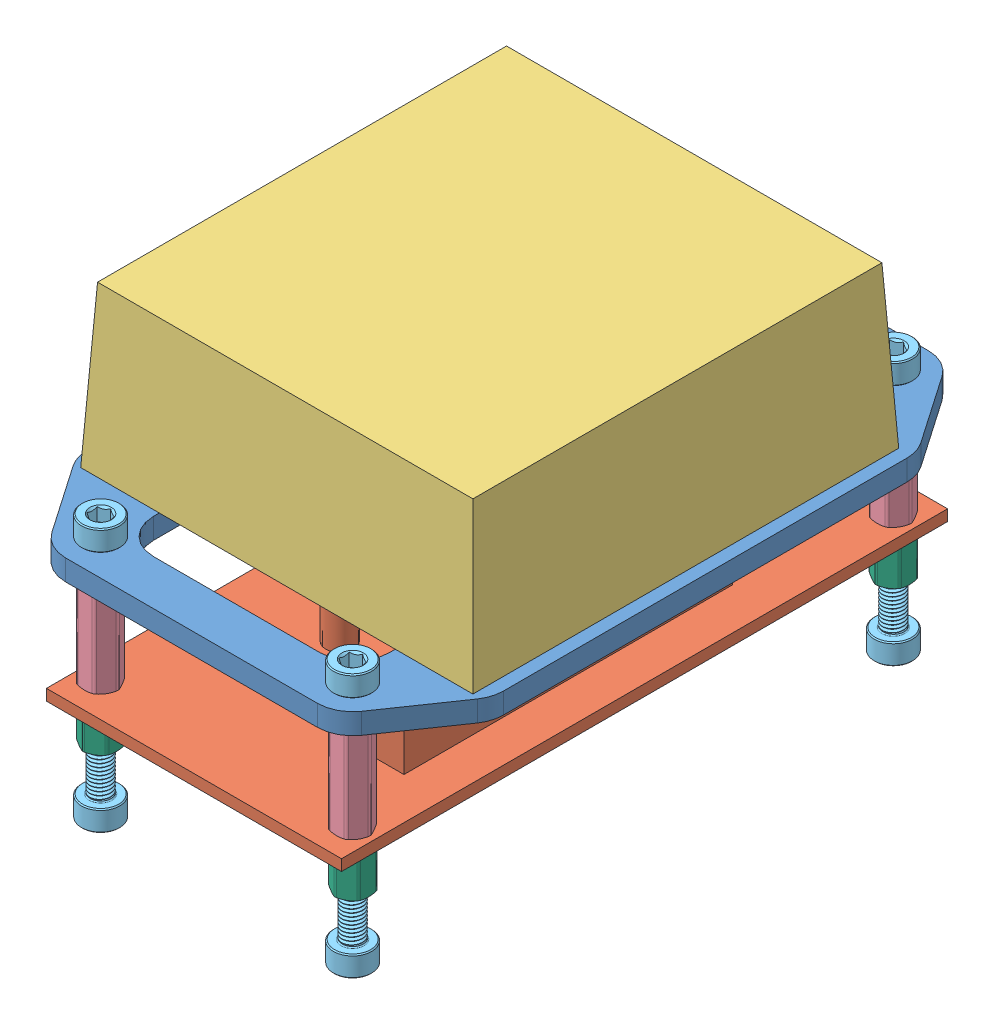
SolidWorks assembly GPS Assembly, configuration Default. Lengths in mm.
Overall size (60 58.13 88).
19 component instances, 6 part files, 36 mates.
Components (placement in the parent):
- GPS Bracket-1: GPS Bracket [Default] at (-19.8291 35.7589 91.6972) size (60 3 88)
- GPS-1: GPS [Default] at (-11.0841 19.1589 91.3522) size (42.51 15.6 87.31)
- GPS Antenna-2: GPS Antenna [Default] at (-18.1499 38.7589 79.3441) size (56.5 23.14 61.34)
- 94868A722_Female Threaded Hex Standoff-1: 94868A722_Female Threaded Hex Standoff [94868A722] at (-7.9791 28.2589 86.6472) x (1 0 0) z (0 -1 0) size (5.06 4.5 15.05)
- 94868A722_Female Threaded Hex Standoff-2: 94868A722_Female Threaded Hex Standoff [94868A722] at (28.3209 28.2589 8.7472) x (1 0 0) z (0 -1 0) size (5.06 4.5 15.05)
- 94868A722_Female Threaded Hex Standoff-3: 94868A722_Female Threaded Hex Standoff [94868A722] at (-7.9791 28.2589 8.7472) x (1 0 0) z (0 -1 0) size (5.06 4.5 15.05)
- 94868A722_Female Threaded Hex Standoff-4: 94868A722_Female Threaded Hex Standoff [94868A722] at (28.3209 28.2589 86.6472) x (1 0 0) z (0 -1 0) size (5.06 4.5 15.05)
- 91290A113_Alloy Steel Socket Head Screw-1: 91290A113_Alloy Steel Socket Head Screw [91290A113] at (-7.9791 36.2589 86.6472) x (1 0 0) z (0 1 0) size (5.5 5.5 11.27)
- 91290A113_Alloy Steel Socket Head Screw-2: 91290A113_Alloy Steel Socket Head Screw [91290A113] at (-7.9791 9.3089 8.7472) x (-0.837169 0 -0.546944) z (0 -1 0) size (5.5 5.5 11.27)
- 91290A113_Alloy Steel Socket Head Screw-3: 91290A113_Alloy Steel Socket Head Screw [91290A113] at (-7.9791 9.3089 86.6472) x (-0.837169 0 -0.546944) z (0 -1 0) size (5.5 5.5 11.27)
- 91290A113_Alloy Steel Socket Head Screw-4: 91290A113_Alloy Steel Socket Head Screw [91290A113] at (28.3209 9.3089 86.6472) x (-0.837169 0 -0.546944) z (0 -1 0) size (5.5 5.5 11.27)
- 91290A113_Alloy Steel Socket Head Screw-5: 91290A113_Alloy Steel Socket Head Screw [91290A113] at (28.3209 36.2589 8.7472) x (1 0 0) z (0 1 0) size (5.5 5.5 11.27)
- 91290A113_Alloy Steel Socket Head Screw-6: 91290A113_Alloy Steel Socket Head Screw [91290A113] at (28.3209 9.3089 8.7472) x (-0.837169 0 -0.546944) z (0 -1 0) size (5.5 5.5 11.27)
- 91290A113_Alloy Steel Socket Head Screw-7: 91290A113_Alloy Steel Socket Head Screw [91290A113] at (-7.9791 36.2589 8.7472) x (1 0 0) z (0 1 0) size (5.5 5.5 11.27)
- 91290A113_Alloy Steel Socket Head Screw-8: 91290A113_Alloy Steel Socket Head Screw [91290A113] at (28.3209 36.2589 86.6472) x (1 0 0) z (0 1 0) size (5.5 5.5 11.27)
- 93655A093_Male-Female Threaded Hex Standoff-1: 93655A093_Male-Female Threaded Hex Standoff [93655A093] at (28.3209 19.1589 8.7472) x (-1 0 0) z (0 -1 0) size (4.5 5.08 10.78)
- 93655A093_Male-Female Threaded Hex Standoff-2: 93655A093_Male-Female Threaded Hex Standoff [93655A093] at (28.3209 19.1589 86.6472) x (-1 0 0) z (0 -1 0) size (4.5 5.08 10.78)
- 93655A093_Male-Female Threaded Hex Standoff-3: 93655A093_Male-Female Threaded Hex Standoff [93655A093] at (-7.9791 19.1589 86.6472) x (-1 0 0) z (0 -1 0) size (4.5 5.08 10.78)
- 93655A093_Male-Female Threaded Hex Standoff-4: 93655A093_Male-Female Threaded Hex Standoff [93655A093] at (-7.9791 19.1589 8.7472) x (-1 0 0) z (0 -1 0) size (4.5 5.08 10.78)
Mates (geometry in assembly coordinates):
- Concentric1: concentric aligned: cylinder of GPS Bracket-1 through (28.3209 38.7589 86.6472) axis (0 -1 0) radius 1.75; cylinder of GPS-1 through (28.3209 20.7589 86.6472) axis (0 -1 0) radius 1.77
- Concentric2: concentric aligned: cylinder of GPS Bracket-1 through (-7.9791 38.7589 8.7472) axis (0 -1 0) radius 1.75; cylinder of GPS-1 through (-7.9791 20.7589 8.7472) axis (0 -1 0) radius 1.77
- Coincident6: coincident anti-aligned: plane of GPS Bracket-1 through (-19.8291 35.7589 91.6972) normal (0 -1 0); plane of 94868A722_Female Threaded Hex Standoff-1 through (-7.9791 35.7589 86.6472) normal (0 1 0)
- Coincident7: coincident anti-aligned: plane of GPS Bracket-1 through (-19.8291 35.7589 91.6972) normal (0 -1 0); plane of 94868A722_Female Threaded Hex Standoff-4 through (28.3209 35.7589 86.6472) normal (0 1 0)
- Coincident8: coincident anti-aligned: plane of GPS Bracket-1 through (-19.8291 35.7589 91.6972) normal (0 -1 0); plane of 94868A722_Female Threaded Hex Standoff-2 through (28.3209 35.7589 8.7472) normal (0 1 0)
- Coincident9: coincident anti-aligned: plane of GPS Bracket-1 through (-19.8291 35.7589 91.6972) normal (0 -1 0); plane of 94868A722_Female Threaded Hex Standoff-3 through (-7.9791 35.7589 8.7472) normal (0 1 0)
- Concentric7: concentric aligned: cylinder of GPS Bracket-1 through (28.3209 38.7589 8.7472) axis (0 -1 0) radius 1.75; cone of 94868A722_Female Threaded Hex Standoff-2 through (28.3209 35.7589 8.7472) axis (0 -1 0)
- Concentric8: concentric aligned: cylinder of GPS Bracket-1 through (-7.9791 38.7589 8.7472) axis (0 -1 0) radius 1.75; cone of 94868A722_Female Threaded Hex Standoff-3 through (-7.9791 35.7589 8.7472) axis (0 -1 0)
- Concentric9: concentric aligned: cylinder of GPS Bracket-1 through (28.3209 38.7589 86.6472) axis (0 -1 0) radius 1.75; cone of 94868A722_Female Threaded Hex Standoff-4 through (28.3209 35.7589 86.6472) axis (0 -1 0)
- Concentric10: concentric aligned: cylinder of GPS Bracket-1 through (-7.9791 38.7589 86.6472) axis (0 -1 0) radius 1.75; cone of 94868A722_Female Threaded Hex Standoff-1 through (-7.9791 35.7589 86.6472) axis (0 -1 0)
- Coincident10: coincident anti-aligned: plane of GPS Bracket-1 through (-19.8291 38.7589 91.6972) normal (0 1 0); plane of GPS Antenna-2 through (-18.1499 38.7589 79.3441) normal (0 -1 0)
- Coincident11: coincident anti-aligned: plane of GPS-1 through (-11.0841 20.7589 91.3522) normal (0 1 0); plane of 94868A722_Female Threaded Hex Standoff-4 through (28.3209 20.7589 86.6472) normal (0 -1 0)
- Coincident12: coincident anti-aligned: plane of GPS Bracket-1 through (-19.8291 38.7589 91.6972) normal (0 1 0); plane of 91290A113_Alloy Steel Socket Head Screw-8 through (28.3209 38.7589 84.0472) normal (0 -1 0)
- Coincident13: coincident anti-aligned: plane of GPS Bracket-1 through (-19.8291 38.7589 91.6972) normal (0 1 0); plane of 91290A113_Alloy Steel Socket Head Screw-1 through (-7.9791 38.7589 84.0472) normal (0 -1 0)
- Coincident14: coincident anti-aligned: plane of GPS Bracket-1 through (-19.8291 38.7589 91.6972) normal (0 1 0); plane of 91290A113_Alloy Steel Socket Head Screw-7 through (-7.9791 38.7589 6.1472) normal (0 -1 0)
- Coincident16: coincident anti-aligned: plane of GPS Bracket-1 through (-19.8291 38.7589 91.6972) normal (0 1 0); plane of 91290A113_Alloy Steel Socket Head Screw-5 through (28.3209 38.7589 6.1472) normal (0 -1 0)
- Concentric12: concentric aligned: cylinder of GPS Bracket-1 through (-7.9791 38.7589 86.6472) axis (0 -1 0) radius 1.75; cylinder of 91290A113_Alloy Steel Socket Head Screw-1 through (-7.9791 30.7589 86.6472) axis (0 -1 0) radius 2.75
- Concentric13: concentric aligned: cylinder of GPS Bracket-1 through (28.3209 38.7589 86.6472) axis (0 -1 0) radius 1.75; cylinder of 91290A113_Alloy Steel Socket Head Screw-8 through (28.3209 30.7589 86.6472) axis (0 -1 0) radius 2.75
- Concentric14: concentric aligned: cylinder of GPS Bracket-1 through (-7.9791 38.7589 8.7472) axis (0 -1 0) radius 1.75; cylinder of 91290A113_Alloy Steel Socket Head Screw-7 through (-7.9791 30.7589 8.7472) axis (0 -1 0) radius 2.75
- Concentric15: concentric aligned: cylinder of GPS Bracket-1 through (28.3209 38.7589 8.7472) axis (0 -1 0) radius 1.75; cylinder of 91290A113_Alloy Steel Socket Head Screw-5 through (28.3209 30.7589 8.7472) axis (0 -1 0) radius 2.75
- Concentric17: concentric anti-aligned: cylinder of GPS-1 through (28.3209 20.7589 8.7472) axis (0 -1 0) radius 1.77; cone of 93655A093_Male-Female Threaded Hex Standoff-1 through (28.3209 19.1589 8.7472) axis (0 1 0)
- Concentric18: concentric anti-aligned: cylinder of GPS-1 through (-7.9791 20.7589 8.7472) axis (0 -1 0) radius 1.77; cone of 93655A093_Male-Female Threaded Hex Standoff-4 through (-7.9791 19.1589 8.7472) axis (0 1 0)
- Concentric19: concentric anti-aligned: cylinder of GPS-1 through (28.3209 20.7589 86.6472) axis (0 -1 0) radius 1.77; cone of 93655A093_Male-Female Threaded Hex Standoff-2 through (28.3209 19.1589 86.6472) axis (0 1 0)
- Concentric20: concentric anti-aligned: cylinder of GPS-1 through (-7.9791 20.7589 86.6472) axis (0 -1 0) radius 1.77; cone of 93655A093_Male-Female Threaded Hex Standoff-3 through (-7.9791 19.1589 86.6472) axis (0 1 0)
- Coincident21: coincident anti-aligned: plane of GPS-1 through (-11.0841 19.1589 91.3522) normal (0 -1 0); plane of 93655A093_Male-Female Threaded Hex Standoff-3 through (-7.9791 19.1589 85.222) normal (0 1 0)
- Coincident22: coincident anti-aligned: plane of GPS-1 through (-11.0841 19.1589 91.3522) normal (0 -1 0); plane of 93655A093_Male-Female Threaded Hex Standoff-2 through (28.3209 19.1589 85.222) normal (0 1 0)
- Coincident23: coincident anti-aligned: plane of GPS-1 through (-11.0841 19.1589 91.3522) normal (0 -1 0); plane of 93655A093_Male-Female Threaded Hex Standoff-4 through (-7.9791 19.1589 7.322) normal (0 1 0)
- Coincident24: coincident anti-aligned: plane of GPS-1 through (-11.0841 19.1589 91.3522) normal (0 -1 0); plane of 93655A093_Male-Female Threaded Hex Standoff-1 through (28.3209 19.1589 7.322) normal (0 1 0)
- Coincident25: coincident aligned: plane of 91290A113_Alloy Steel Socket Head Screw-3 through (-6.5571 6.8089 84.4706) normal (0 1 0); plane of 91290A113_Alloy Steel Socket Head Screw-4 through (29.7429 6.8089 84.4706) normal (0 1 0)
- Coincident26: coincident aligned: plane of 91290A113_Alloy Steel Socket Head Screw-2 through (-6.5571 6.8089 6.5706) normal (0 1 0); plane of 91290A113_Alloy Steel Socket Head Screw-4 through (29.7429 6.8089 84.4706) normal (0 1 0)
- Coincident27: coincident aligned: plane of 91290A113_Alloy Steel Socket Head Screw-2 through (-6.5571 6.8089 6.5706) normal (0 1 0); plane of 91290A113_Alloy Steel Socket Head Screw-6 through (29.7429 6.8089 6.5706) normal (0 1 0)
- Distance1: distance = 6.35 mm anti-aligned: plane of 91290A113_Alloy Steel Socket Head Screw-6 through (29.7429 6.8089 6.5706) normal (0 1 0); plane of 93655A093_Male-Female Threaded Hex Standoff-3 through (-7.9791 13.1589 84.8972) normal (0 -1 0)
- Concentric21: concentric aligned: cylinder of 91290A113_Alloy Steel Socket Head Screw-3 through (-7.9791 14.8089 86.6472) axis (0 1 0) radius 2.75; cone of 93655A093_Male-Female Threaded Hex Standoff-3 through (-7.9791 13.1589 86.6472) axis (0 1 0)
- Concentric22: concentric aligned: cylinder of 91290A113_Alloy Steel Socket Head Screw-4 through (28.3209 14.8089 86.6472) axis (0 1 0) radius 2.75; cone of 93655A093_Male-Female Threaded Hex Standoff-2 through (28.3209 13.1589 86.6472) axis (0 1 0)
- Concentric23: concentric aligned: cylinder of 91290A113_Alloy Steel Socket Head Screw-2 through (-7.9791 14.8089 8.7472) axis (0 1 0) radius 2.75; cone of 93655A093_Male-Female Threaded Hex Standoff-4 through (-7.9791 13.1589 8.7472) axis (0 1 0)
- Concentric24: concentric aligned: cylinder of 91290A113_Alloy Steel Socket Head Screw-6 through (28.3209 14.8089 8.7472) axis (0 1 0) radius 2.75; cone of 93655A093_Male-Female Threaded Hex Standoff-1 through (28.3209 13.1589 8.7472) axis (0 1 0)
